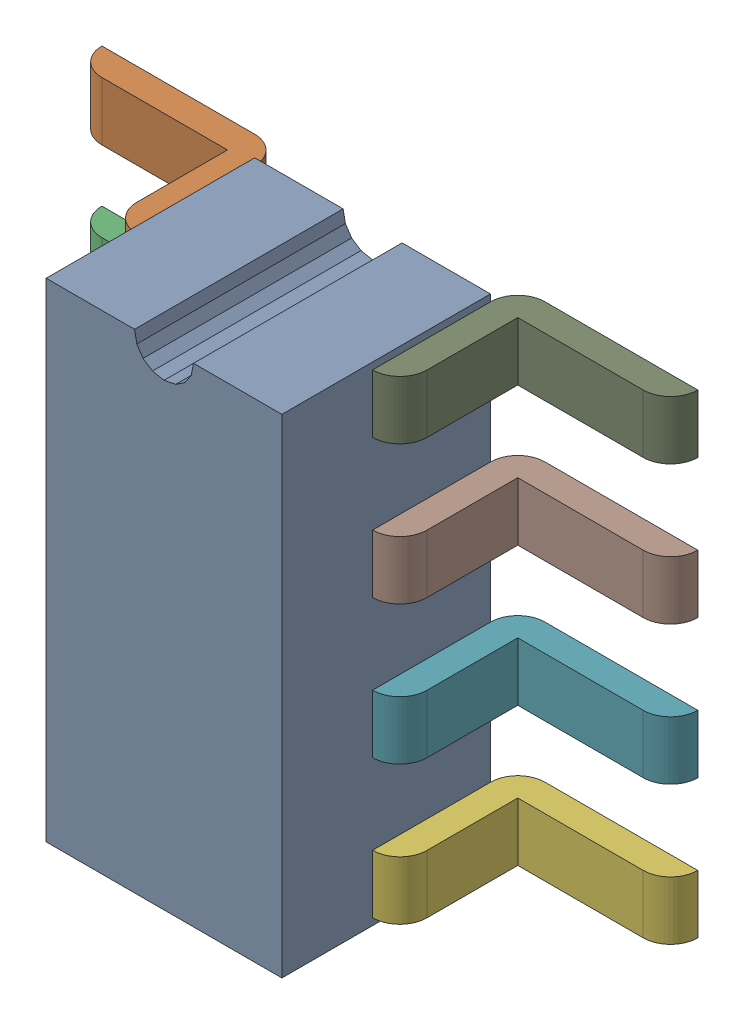
SolidWorks assembly Open CASCADE STEP translator 6.8 1.16.1, configuration Défaut. Lengths in mm.
Overall size (5.46 4.47 2.16).
9 component instances, 9 part files, 0 mates.
Components (placement in the parent):
- Body_1_9-1: Body_1_9 [Défaut] at origin size (2.16 4.47 1.91)
- Pin_1_6-1: Pin_1_6 [Défaut] at origin size (1.65 0.54 1.33)
- Pin_2_6-1: Pin_2_6 [Défaut] at origin size (1.65 0.54 1.33)
- Pin_3_4-1: Pin_3_4 [Défaut] at origin size (1.65 0.54 1.33)
- Pin_4_3-1: Pin_4_3 [Défaut] at origin size (1.65 0.54 1.33)
- Pin_5_3-1: Pin_5_3 [Défaut] at (5.207 -3.81 0) x (-1 0 0) z (0 0 1) size (1.65 0.54 1.33)
- Pin_6_3-1: Pin_6_3 [Défaut] at (5.207 -1.27 0) x (-1 0 0) z (0 0 1) size (1.65 0.54 1.33)
- Pin_7-1: Pin_7 [Défaut] at (5.207 1.27 0) x (-1 0 0) z (0 0 1) size (1.65 0.54 1.33)
- Pin_8-1: Pin_8 [Défaut] at (5.207 3.81 0) x (-1 0 0) z (0 0 1) size (1.65 0.54 1.33)
